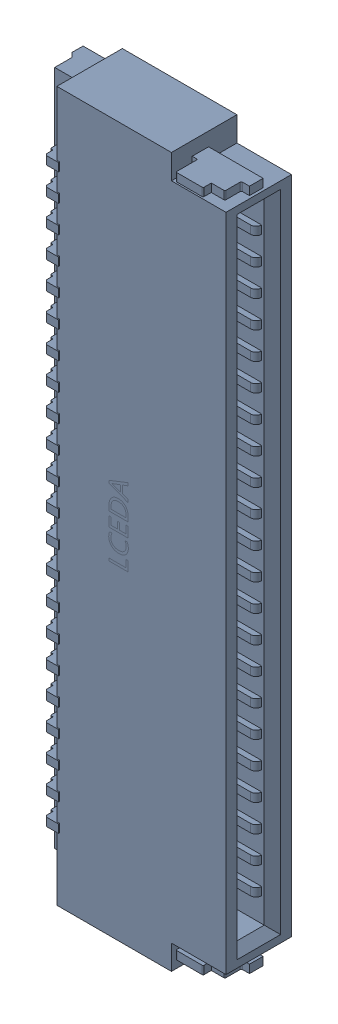
SolidWorks assembly FPC2, configuration Défaut. Lengths in mm.
Overall size (3.8 13 1.23).
4 component instances, 1 part files, 0 mates.
Components (placement in the parent):
- FH34SRJ-22S-0.5SH(50)-1: FH34SRJ-22S-0.5SH(50) [Défaut] at (70.7965 -14.9677 -0.4818) x (0 -1 0) z (0 0 -1) size (13 3.8 1.23)
  - FPC1.step_745-1: FPC1.step_745 [Défaut] at (8.84 -9.4501 1.6001) size (13 3.8 1.23)
    - FFC-SMD_22P-P0.50_HRS_FH34SRJ-22S-0.5SH.step-1: FFC-SMD_22P-P0.50_HRS_FH34SRJ-22S-0.5SH.step [Défaut] at origin size (13 3.8 1.23)
      - SOLID.step_747-1: SOLID.step_747 [Défaut] at origin size (13 3.8 1.23)
